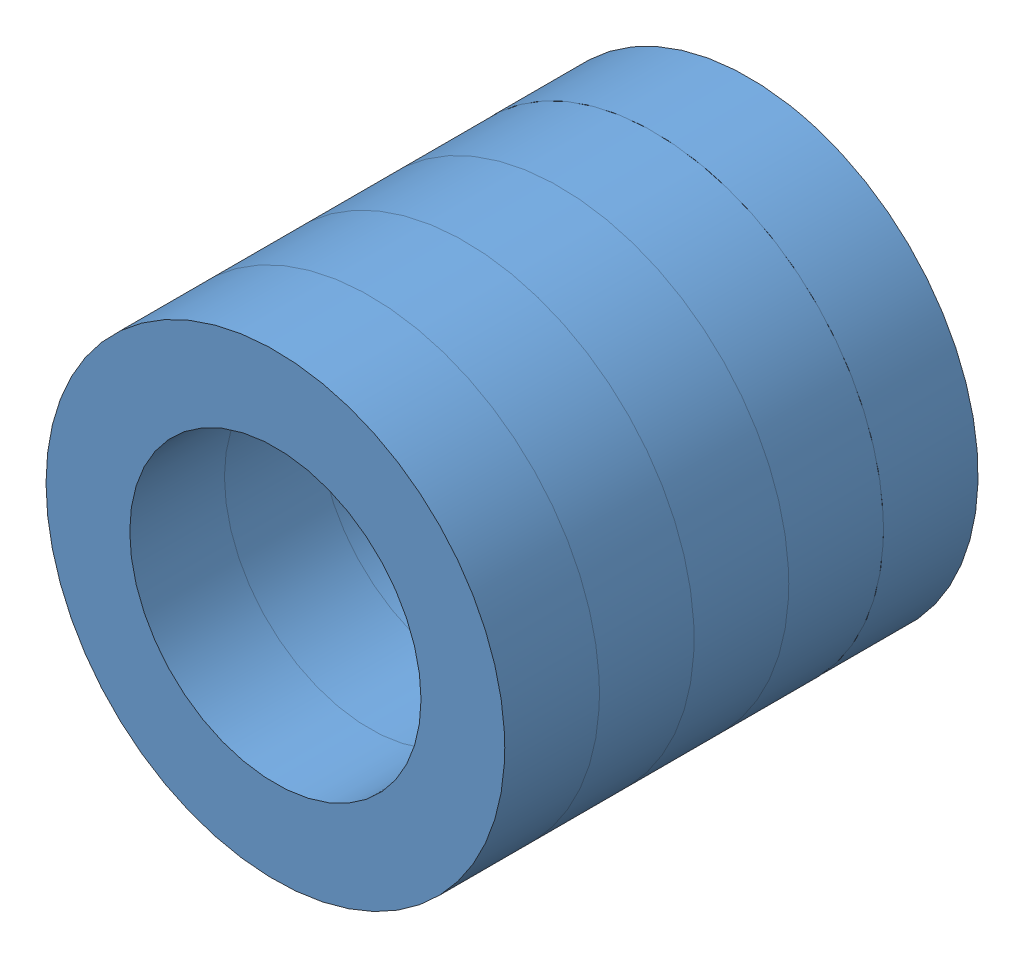
SolidWorks assembly Assem1, configuration Default. Lengths in mm.
Overall size (30.42 30.42 26).
5 component instances, 1 part files, 11 mates.
Components (placement in the parent):
- 25x16x5 neodymium bearing-3: 25x16x5 neodymium bearing [Default] at origin size (25.2 25.2 5.2)
- 25x16x5 neodymium bearing-1: 25x16x5 neodymium bearing [Default] at (0 0 -15.6) size (25.2 25.2 5.2)
- 25x16x5 neodymium bearing-2: 25x16x5 neodymium bearing [Default] at (0 0 -5.2) size (25.2 25.2 5.2)
- 25x16x5 neodymium bearing-4: 25x16x5 neodymium bearing [Default] at (0 0 -10.4) size (25.2 25.2 5.2)
- 25x16x5 neodymium bearing-5: 25x16x5 neodymium bearing [Default] at (0 0 -20.8) x (0.235075 0.971977 0) z (0 0 1) size (25.2 25.2 5.2)
Mates (geometry in assembly coordinates):
- Concentric1: concentric aligned: cylinder of 25x16x5 neodymium bearing-2 through (12.9759 0 0) axis (0 0 -1) radius 8; cylinder of 25x16x5 neodymium bearing-3 through (12.9759 0 5.2) axis (0 0 -1) radius 8
- Concentric2: concentric aligned: cylinder of 25x16x5 neodymium bearing-3 through (12.9759 0 5.2) axis (0 0 -1) radius 8; cylinder of 25x16x5 neodymium bearing-4 through (12.9759 0 -5.2) axis (0 0 -1) radius 8
- Concentric3: concentric aligned: cylinder of 25x16x5 neodymium bearing-1 through (12.9759 0 -10.4) axis (0 0 -1) radius 8; cylinder of 25x16x5 neodymium bearing-3 through (12.9759 0 5.2) axis (0 0 -1) radius 8
- Concentric4: concentric aligned: cylinder of 25x16x5 neodymium bearing-3 through (12.9759 0 5.2) axis (0 0 -1) radius 8; cylinder of 25x16x5 neodymium bearing-5 through (12.9759 0 -15.6) axis (0 0 -1) radius 8
- Coincident1: coincident anti-aligned: plane of 25x16x5 neodymium bearing-2 through (12.9759 0 0) normal (0 0 1); plane of 25x16x5 neodymium bearing-3 through (12.9759 0 0) normal (0 0 -1)
- Coincident2: coincident anti-aligned: plane of 25x16x5 neodymium bearing-2 through (12.9759 0 -5.2) normal (0 0 -1); plane of 25x16x5 neodymium bearing-4 through (12.9759 0 -5.2) normal (0 0 1)
- Coincident3: coincident anti-aligned: plane of 25x16x5 neodymium bearing-1 through (12.9759 0 -10.4) normal (0 0 1); plane of 25x16x5 neodymium bearing-4 through (12.9759 0 -10.4) normal (0 0 -1)
- Coincident4: coincident anti-aligned: plane of 25x16x5 neodymium bearing-1 through (12.9759 0 -15.6) normal (0 0 -1); plane of 25x16x5 neodymium bearing-5 through (12.9759 0 -15.6) normal (0 0 1)
- Coincident6: coincident aligned: plane of 25x16x5 neodymium bearing-3 through (0 0 0) normal (0 0 1); plane of assembly
- Coincident7: coincident aligned: plane of 25x16x5 neodymium bearing-3 through (0 0 0) normal (0 1 0); plane of assembly
- Coincident8: coincident aligned: plane of 25x16x5 neodymium bearing-3 through (0 0 0) normal (1 0 0); plane of assembly
